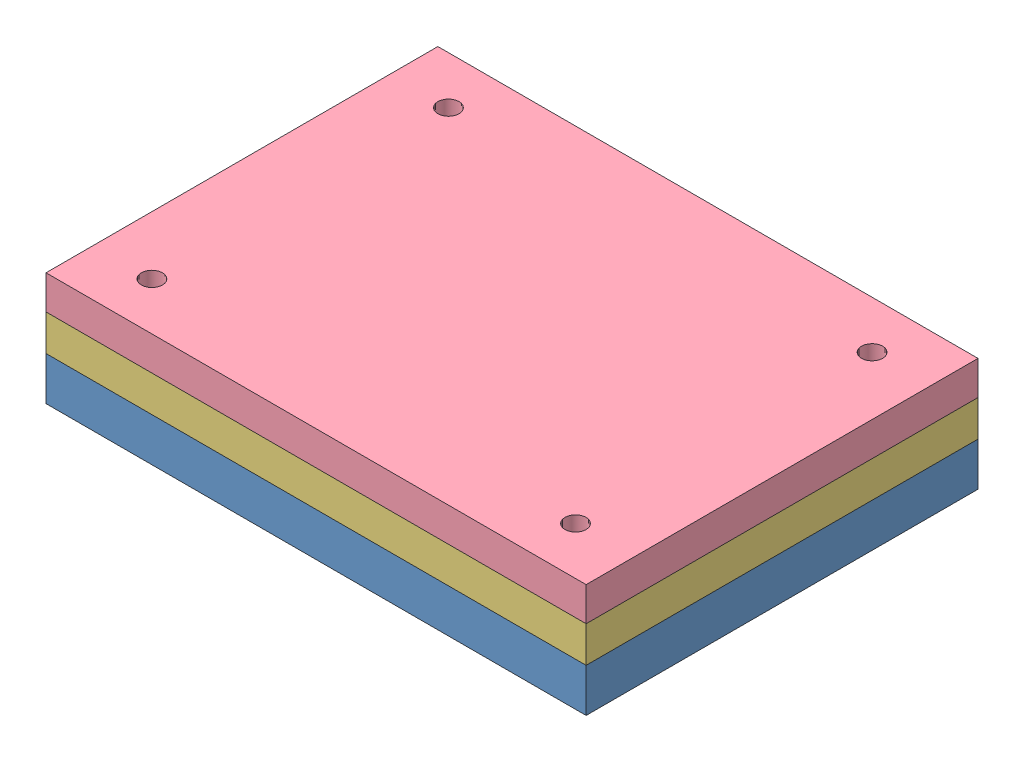
SolidWorks assembly venti mold, configuration Default. Lengths in mm.
Overall size (255 53.5 185).
4 component instances, 4 part files, 9 mates.
Components (placement in the parent):
- ventin cavity-1: ventin cavity [Default] at (74.6384 116.1657 211.4674) size (255 20.5 185)
- ventilator-1: ventilator [Default] at (74.6384 156.1657 211.4674) size (175 22 125) (hidden)
- venti hole-2: venti hole [Default] at (74.6384 136.6657 211.4674) x (-1 0 0) z (0 0 1) size (255 17 185)
- venti core-1: venti core [Default] at (74.6384 169.6657 211.4674) x (-1 0 0) z (0 0 1) size (255 33 185)
Mates (geometry in assembly coordinates):
- Coincident17: coincident aligned: plane of ventin cavity-1 through (-52.8616 136.6657 118.9674) normal (0 1 0); plane of ventilator-1 through (74.6384 136.6657 211.4674) normal (0 1 0)
- Concentric1: concentric anti-aligned: circle of ventin cavity-1; circle of ventilator-1
- Concentric2: concentric anti-aligned: circle of ventin cavity-1; circle of ventilator-1
- Coincident24: coincident anti-aligned: plane of ventin cavity-1 through (-52.8616 136.6657 118.9674) normal (0 1 0); plane of venti hole-2 through (74.6384 136.6657 211.4674) normal (0 -1 0)
- Coincident25: coincident anti-aligned: circle of ventin cavity-1; circle of venti hole-2
- Coincident26: coincident anti-aligned: circle of ventin cavity-1; circle of venti hole-2
- Coincident27: coincident anti-aligned: plane of venti hole-2 through (74.6384 153.6657 211.4674) normal (0 1 0); plane of venti core-1 through (202.1384 153.6657 118.9674) normal (0 -1 0)
- Coincident28: coincident aligned: circle of venti hole-2; circle of venti core-1
- Coincident29: coincident aligned: circle of venti hole-2; circle of venti core-1
